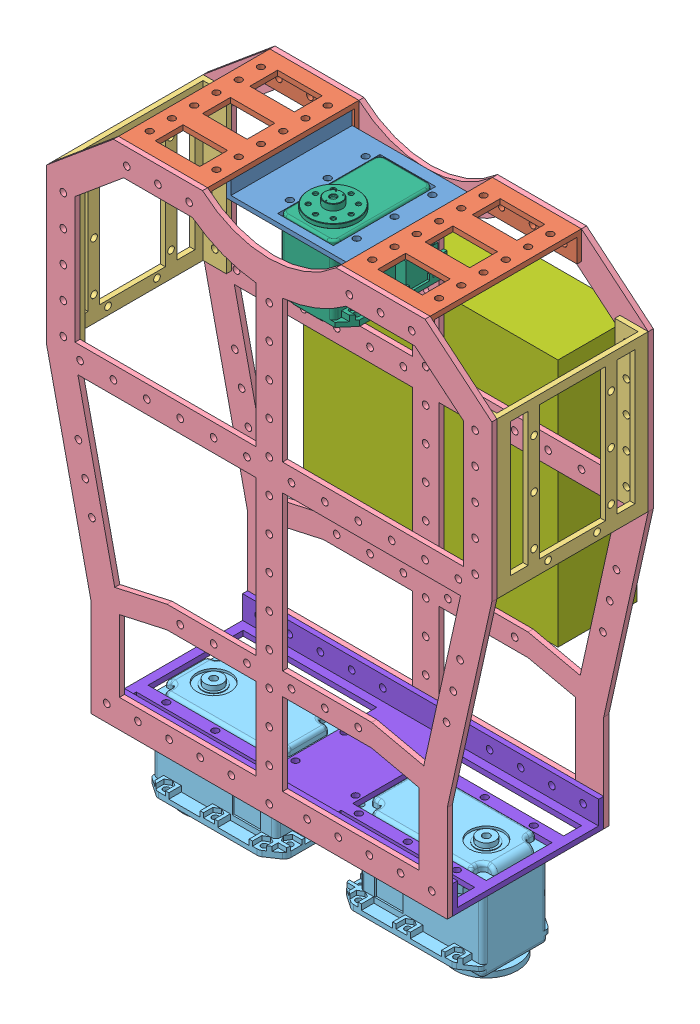
SolidWorks assembly torso_no_arm_motor, configuration Default. Lengths in mm.
Overall size (200 273.51 155.87).
12 component instances, 8 part files, 36 mates.
Components (placement in the parent):
- torso_frame_head-1: torso_frame_head [Default] at (0 -3.827 -35) size (76 8 58.5)
- torso_frame_link-1: torso_frame_link [Default] at (-50 -6.241 0) x (0 0 1) z (-1 0 0) size (75.11 12.7 53.47)
- torso_frame_motor-1: torso_frame_motor [Default] at (-98.857 -88.541 0) x (0 0 1) z (-1 0 0) size (68 70 36.25)
- torso_main-1: torso_main [Default] at (0 0 34) size (200 228.5 2.29)
- torso_main-2: torso_main [Default] at (0 0 -36.286) size (200 228.5 2.29)
- torso_frame_link-2: torso_frame_link [Default] at (50 -6.241 0) x (0 0 1) z (-1 0 0) size (75.11 12.7 53.47)
- torso_frame_motor-2: torso_frame_motor [Default] at (98.857 -88.541 0) x (0 0 -1) z (1 0 0) size (68 70 36.25)
- MX-64T_step-3: MX-64T_step [Default] at (61.25 -239.048 0) x (0 0 -1) z (0 -1 0) size (40.2 62.1 50)
- MX-64T_step-4: MX-64T_step [Default] at (-61.25 -239.048 0) x (0 0 1) z (0 -1 0) size (40.2 62.1 50)
- MX28_step-1: MX28_step [Default] at (11.9078 -61.4181 -29.7938) x (-1 0 0) z (0 1 0) size (35.6 50.71 42.6)
- nuc-1: nuc [Default] at (0 -108.0269 -54.066) size (114.3 111.76 35.56)
- torso_frame_link_new-1: torso_frame_link_new [Default] at (0 -204.0668 0) x (0 0 -1) z (-1 0 0) size (148.76 12.7 166.17)
Mates (geometry in assembly coordinates):
- Concentric1: concentric aligned: cylinder of torso_frame_link-1 through (-64 -1.034 34) axis (0 0 1) radius 1.5; cylinder of torso_main-1 through (-64 -1.034 36.286) axis (0 0 1) radius 1.5
- Concentric2: concentric aligned: cylinder of torso_frame_link-1 through (-36 -1.034 34) axis (0 0 1) radius 1.5; cylinder of torso_main-1 through (-36 -1.034 36.286) axis (0 0 1) radius 1.5
- Coincident1: coincident anti-aligned: plane of torso_frame_link-1 through (-70 -6.241 34) normal (0 0 1); plane of torso_main-1 through (0 40 34) normal (0 0 -1)
- Concentric3: concentric aligned: cylinder of torso_frame_link-1 through (-64 -1.034 34) axis (0 0 1) radius 1.5; cylinder of torso_main-2 through (-64 -1.034 -34) axis (0 0 1) radius 1.5
- Concentric4: concentric aligned: cylinder of torso_frame_link-1 through (-36 -1.034 34) axis (0 0 1) radius 1.5; cylinder of torso_main-2 through (-36 -1.034 -34) axis (0 0 1) radius 1.5
- Coincident2: coincident anti-aligned: plane of torso_frame_link-1 through (-70 -6.241 -34) normal (0 0 -1); plane of torso_main-2 through (0 40 -34) normal (0 0 1)
- Concentric5: concentric aligned: cylinder of torso_frame_motor-1 through (-92.507 -25.541 -34) axis (0 0 -1) radius 1.5; cylinder of torso_main-2 through (-92.507 -25.541 -36.286) axis (0 0 -1) radius 1.5
- Concentric6: concentric aligned: cylinder of torso_frame_motor-1 through (-92.507 -81.541 -34) axis (0 0 -1) radius 1.5; cylinder of torso_main-2 through (-92.507 -81.541 -36.286) axis (0 0 -1) radius 1.5
- Coincident3: coincident anti-aligned: plane of torso_frame_motor-1 through (-97.714 -88.541 -34) normal (0 0 -1); plane of torso_main-2 through (0 40 -34) normal (0 0 1)
- Coincident4: coincident anti-aligned: plane of torso_frame_head-1 through (-30 4.173 15) normal (0 1 0); plane of torso_frame_link-1 through (-70 4.173 -32) normal (0 -1 0)
- Concentric9: concentric aligned: cylinder of torso_main-2 through (36 -1.034 -34) axis (0 0 1) radius 1.5; cylinder of torso_frame_link-2 through (36 -1.034 34) axis (0 0 1) radius 1.5
- Concentric10: concentric aligned: cylinder of torso_main-2 through (64 -1.034 -34) axis (0 0 1) radius 1.5; cylinder of torso_frame_link-2 through (64 -1.034 34) axis (0 0 1) radius 1.5
- Coincident5: coincident anti-aligned: plane of torso_main-2 through (0 40 -34) normal (0 0 1); plane of torso_frame_link-2 through (30 -6.241 -34) normal (0 0 -1)
- Concentric11: concentric anti-aligned: cylinder of torso_main-1 through (92.507 -25.541 34) axis (0 0 -1) radius 1.5; cylinder of torso_frame_motor-2 through (92.507 -25.541 34) axis (0 0 1) radius 1.5
- Concentric12: concentric anti-aligned: cylinder of torso_main-1 through (92.507 -81.541 34) axis (0 0 -1) radius 1.5; cylinder of torso_frame_motor-2 through (92.507 -81.541 34) axis (0 0 1) radius 1.5
- Coincident6: coincident anti-aligned: plane of torso_main-1 through (0 40 34) normal (0 0 -1); plane of torso_frame_motor-2 through (97.714 -88.541 34) normal (0 0 1)
- Concentric25: concentric aligned: cylinder of torso_frame_head-1 through (35 4.173 -25) axis (0 1 0) radius 1.5; cylinder of torso_frame_link-2 through (35 6.459 -25) axis (0 1 0) radius 1.5
- Concentric26: concentric aligned: cylinder of torso_frame_head-1 through (35 4.173 -5) axis (0 1 0) radius 1.5; cylinder of torso_frame_link-2 through (35 6.459 -5) axis (0 1 0) radius 1.5
- Concentric38: concentric anti-aligned: cylinder of torso_frame_head-1 through (-15 -1.827 12) axis (0 1 0) radius 1.5; cylinder of MX28_step-1 through (-15 -18.827 12) axis (0 -1 0) radius 1.35
- Concentric39: concentric anti-aligned: cylinder of torso_frame_head-1 through (15 -1.827 12) axis (0 1 0) radius 1.5; cylinder of MX28_step-1 through (15 -18.827 12) axis (0 -1 0) radius 1.35
- Coincident15: coincident anti-aligned: plane of torso_frame_head-1 through (-32 -3.827 15) normal (0 -1 0); plane of MX28_step-1 through (0 -3.827 7.5) normal (0 1 0)
- Distance1: distance = 34 mm anti-aligned: plane of torso_main-1 through (0 40 34) normal (0 0 -1); plane of assembly through (0 0 0) normal (0 0 1)
- Coincident19: coincident aligned: plane of torso_main-1 through (0 0 34) normal (1 0 0); plane of assembly through (0 0 0) normal (1 0 0)
- Coincident20: coincident aligned: plane of torso_main-1 through (0 0 34) normal (0 1 0); plane of assembly through (0 0 0) normal (0 1 0)
- Coincident22: coincident aligned: plane of torso_frame_head-1 through (0 -3.827 -35) normal (1 0 0); plane of nuc-1 through (0 -108.0269 -54.066) normal (1 0 0)
- Coincident23: coincident: plane of nuc-1 through (-57.15 -52.1469 -36.286) normal (0 1 0); line of assembly
- Coincident24: coincident anti-aligned: plane of torso_main-2 through (0 40 -36.286) normal (0 0 -1); plane of nuc-1 through (0 -108.0269 -36.286) normal (0 0 1)
- Coincident25: coincident anti-aligned: plane of torso_main-2 through (0 40 -34) normal (0 0 1); plane of torso_frame_link_new-1 through (-80 -222.048 -34) normal (0 0 -1)
- Concentric40: concentric anti-aligned: cylinder of torso_main-1 through (-73 -214.548 34) axis (0 0 -1) radius 1.5; cylinder of torso_frame_link_new-1 through (-73 -214.548 34) axis (0 0 1) radius 1.5
- Concentric41: concentric anti-aligned: cylinder of torso_main-1 through (73 -214.548 34) axis (0 0 -1) radius 1.5; cylinder of torso_frame_link_new-1 through (73 -214.548 34) axis (0 0 1) radius 1.5
- Concentric42: concentric anti-aligned: cylinder of MX-64T_step-3 through (65.25 -239.048 17.3) axis (0 1 0) radius 1.35; cylinder of torso_frame_link_new-1 through (65.25 -62.048 17.3) axis (0 -1 0) radius 1.5
- Concentric43: concentric anti-aligned: cylinder of MX-64T_step-3 through (21.25 -226.548 -17.3) axis (0 1 0) radius 1.35; cylinder of torso_frame_link_new-1 through (21.25 -62.048 -17.3) axis (0 -1 0) radius 1.5
- Coincident26: coincident anti-aligned: plane of MX-64T_step-3 through (61.25 -222.048 0) normal (0 1 0); plane of torso_frame_link_new-1 through (-80 -222.048 34) normal (0 -1 0)
- Concentric44: concentric anti-aligned: cylinder of MX-64T_step-4 through (-65.25 -239.048 -17.3) axis (0 1 0) radius 1.35; cylinder of torso_frame_link_new-1 through (-65.25 -62.048 -17.3) axis (0 -1 0) radius 1.5
- Concentric45: concentric anti-aligned: cylinder of MX-64T_step-4 through (-21.25 -226.548 17.3) axis (0 1 0) radius 1.35; cylinder of torso_frame_link_new-1 through (-21.25 -62.048 17.3) axis (0 -1 0) radius 1.5
- Coincident29: coincident anti-aligned: plane of MX-64T_step-4 through (-61.25 -222.048 0) normal (0 1 0); plane of torso_frame_link_new-1 through (-80 -222.048 34) normal (0 -1 0)
